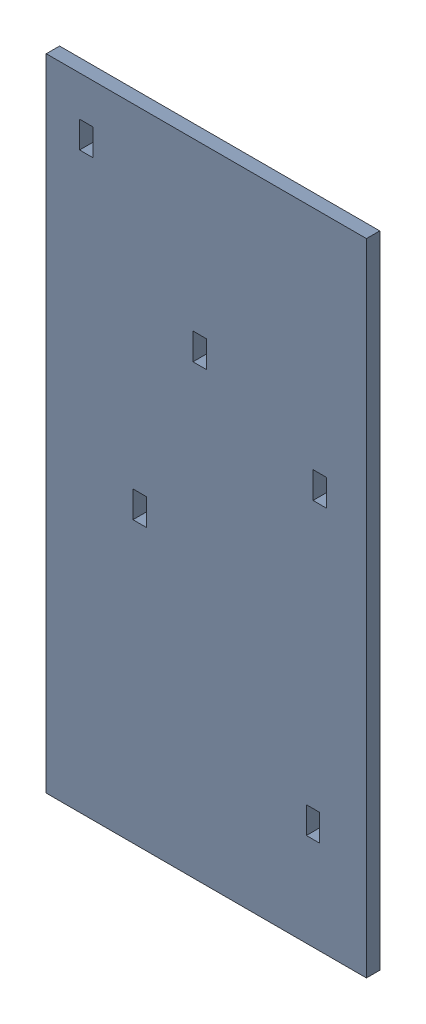
SolidWorks assembly ASSM_Switch_Panel, configuration Default. Lengths in mm.
Overall size (609.6 1219.2 50.8).
6 component instances, 2 part files, 10 mates.
Components (placement in the parent):
- Switch_Panel-1: Switch_Panel [Default] at (-105.9369 74.5876 5.2278) size (609.6 1219.2 25.4)
- Switch-1: Switch [Default] at (-334.5369 582.5876 -20.1722) x (0 0 -1) z (1 0 0) size (27.3 3.81 19.05)
- Switch-2: Switch [Default] at (-118.6369 341.2876 -20.1722) x (0 0 -1) z (1 0 0) size (27.3 3.81 19.05)
- Switch-3: Switch [Default] at (109.9631 237.2835 -14.9075) x (0 0.810707 -0.585453) z (-1 0 0) size (27.3 3.81 19.05)
- Switch-4: Switch [Default] at (-232.9369 23.7876 -20.1722) x (0 0 -1) z (1 0 0) size (27.3 3.81 19.05)
- Switch-5: Switch [Default] at (97.2631 -331.8124 -20.1722) x (0 0 -1) z (1 0 0) size (27.3 3.81 19.05)
Mates (geometry in assembly coordinates):
- Concentric1: concentric: line of Switch_Panel-1 through (122.6631 226.9876 -7.4722) axis (-1 0 0); cylinder of Switch-3 through (100.4381 226.9876 -7.4722) axis (1 0 0) radius 1.905
- Width1: width anti-aligned: plane of Switch_Panel-1 through (97.2631 74.5876 17.9278) normal (1 0 0); plane of Switch-3 through (122.6631 74.5876 17.9278) normal (-1 0 0); plane of Switch_Panel-1 through (100.4381 237.2835 -14.9075) normal (-1 0 0); plane of Switch-3 through (119.4881 237.2835 -14.9075) normal (1 0 0)
- Concentric2: concentric: line of Switch_Panel-1 through (-131.3369 341.2876 -7.4722) axis (1 0 0); cylinder of Switch-2 through (-109.1119 341.2876 -7.4722) axis (-1 0 0) radius 1.905
- Width2: width anti-aligned: plane of Switch-2 through (-128.1619 341.2876 -20.1722) normal (-1 0 0); plane of Switch_Panel-1 through (-109.1119 341.2876 -20.1722) normal (1 0 0); plane of Switch-2 through (-131.3369 74.5876 17.9278) normal (1 0 0); plane of Switch_Panel-1 through (-105.9369 74.5876 17.9278) normal (-1 0 0)
- Concentric3: concentric: line of Switch_Panel-1 through (-347.2369 582.5876 -7.4722) axis (1 0 0); cylinder of Switch-1 through (-325.0119 582.5876 -7.4722) axis (-1 0 0) radius 1.905
- Width3: width anti-aligned: plane of Switch-1 through (-325.0119 582.5876 -20.1722) normal (1 0 0); plane of Switch_Panel-1 through (-344.0619 582.5876 -20.1722) normal (-1 0 0); plane of Switch-1 through (-321.8369 74.5876 17.9278) normal (-1 0 0); plane of Switch_Panel-1 through (-347.2369 74.5876 17.9278) normal (1 0 0)
- Concentric4: concentric: line of Switch_Panel-1 through (84.5631 -331.8124 -7.4722) axis (1 0 0); cylinder of Switch-5 through (106.7881 -331.8124 -7.4722) axis (-1 0 0) radius 1.905
- Width4: width anti-aligned: plane of Switch_Panel-1 through (84.5631 74.5876 17.9278) normal (1 0 0); plane of Switch-5 through (109.9631 74.5876 17.9278) normal (-1 0 0); plane of Switch_Panel-1 through (87.7381 -331.8124 -20.1722) normal (-1 0 0); plane of Switch-5 through (106.7881 -331.8124 -20.1722) normal (1 0 0)
- Concentric5: concentric: cylinder of Switch-4 through (-223.4119 23.7876 -7.4722) axis (-1 0 0) radius 1.905; line of Switch_Panel-1 through (-245.6369 23.7876 -7.4722) axis (1 0 0)
- Width5: width anti-aligned: plane of Switch-4 through (-223.4119 23.7876 -20.1722) normal (1 0 0); plane of Switch_Panel-1 through (-242.4619 23.7876 -20.1722) normal (-1 0 0); plane of Switch-4 through (-220.2369 74.5876 17.9278) normal (-1 0 0); plane of Switch_Panel-1 through (-245.6369 74.5876 17.9278) normal (1 0 0)
